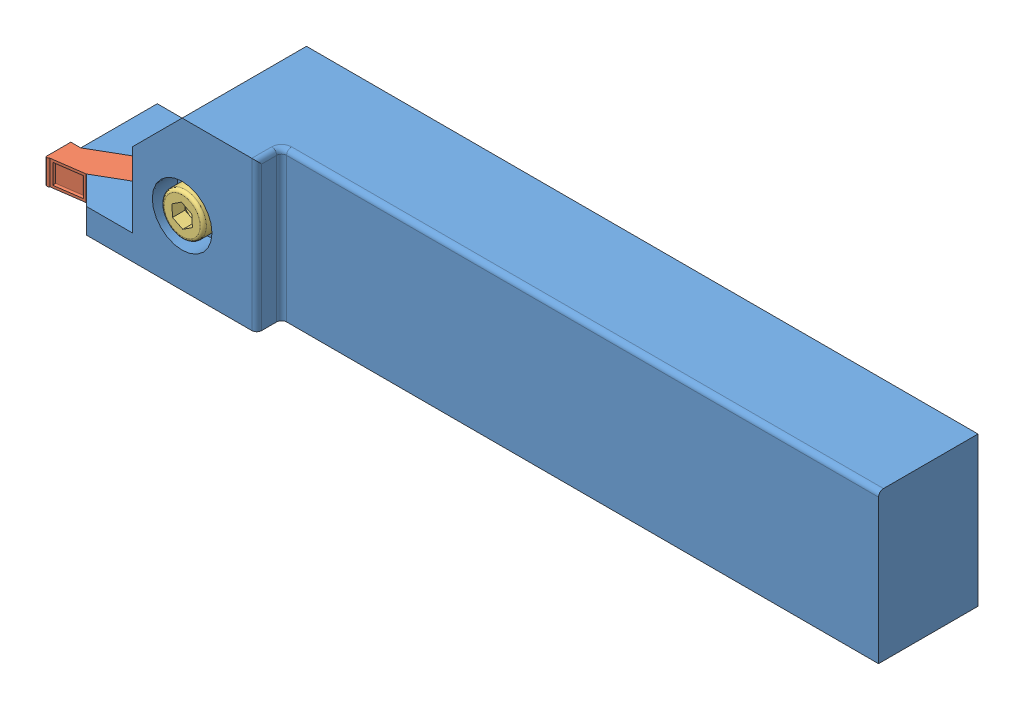
SolidWorks assembly 切断刀, configuration 默认. Lengths in mm.
Overall size (139.16 30 29.87).
3 component instances, 3 part files, 5 mates.
Components (placement in the parent):
- 切断刀刀柄-1: 切断刀刀柄 [默认] at (18.1542 12.0268 -12.5) size (135 30 25)
- 切断刀刀片-3: 切断刀刀片 [默认] at (-84.6401 2.0268 7.8462) x (0.866025 0 0.5) z (0 -1 0) size (21.49 20.95 5)
- hexagon socket head cap screws gb-1: hexagon socket head cap screws gb [GB_FASTENER_SCREWS_HSHCS M5X8-N] at (-56.8458 10.0268 12.5) x (0 0 -1) z (0.056624 -0.998396 0) size (13 8.5 8.5)
Mates (geometry in assembly coordinates):
- 重合13: coincident anti-aligned: plane of 切断刀刀柄-1 through (-78.1856 17.0268 -2.1237) normal (0.5 0 0.866025); plane of 切断刀刀片-3 through (-75.3848 -2.9732 -3.7407) normal (-0.5 0 -0.866025)
- 重合14: coincident aligned: plane of 切断刀刀柄-1 through (-41.8458 -2.9732 7.5) normal (0 -1 0); plane of 切断刀刀片-3 through (-88.5444 -2.9732 7.4674) normal (0 -1 0)
- 重合16: coincident anti-aligned: line of 切断刀刀柄-1 through (-86.8458 2.0268 2.8763) axis (0 -1 0); line of 切断刀刀片-3 through (-86.8458 -2.9732 2.8763) axis (0 1 0)
- 同心1: concentric aligned: cylinder of 切断刀刀柄-1 through (-56.8458 10.0268 12.5) axis (0 0 1) radius 6; cylinder of hexagon socket head cap screws gb-1 through (-56.8458 10.0268 -0.5) axis (0 0 1) radius 2.5
- 重合17: coincident anti-aligned: plane of 切断刀刀柄-1 through (-52.8458 10.0268 7.5) normal (0 0 1); plane of hexagon socket head cap screws gb-1 through (-56.8458 10.0268 7.5) normal (0 0 -1)
